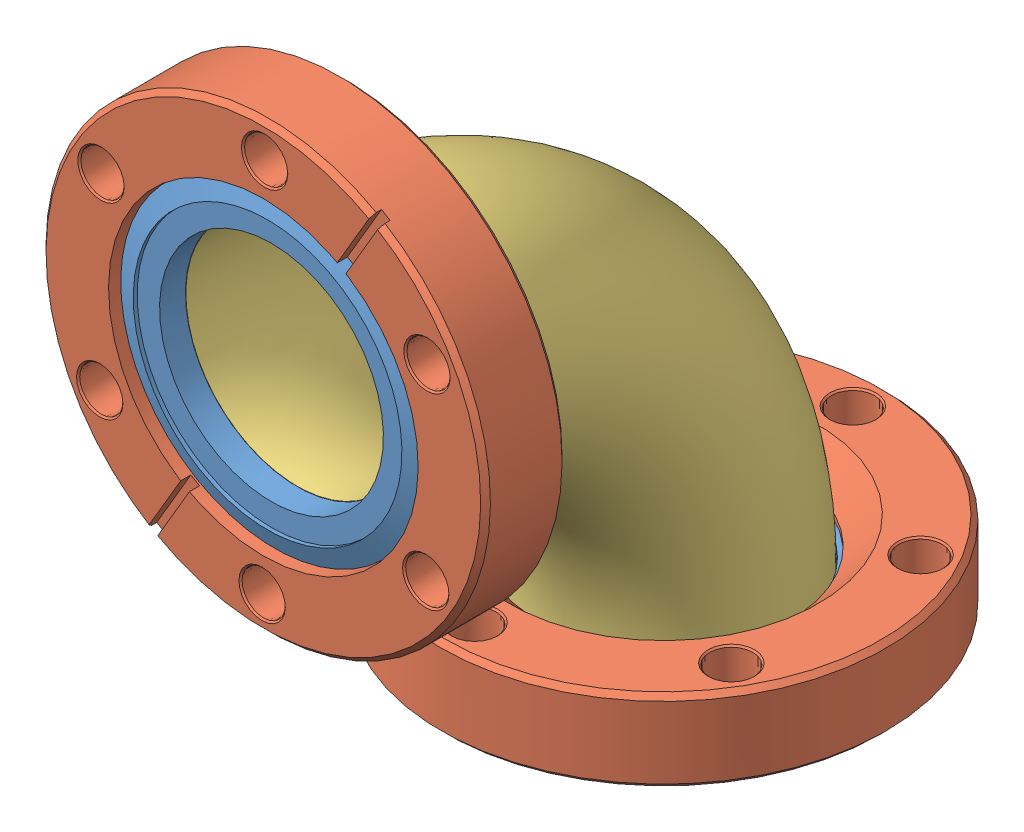
SolidWorks assembly 403002, configuration Default. Lengths in mm.
Overall size (94.6 97.36 109.76).
5 component instances, 3 part files, 0 mates.
Components (placement in the parent):
- 910014-1: 910014 [Default] at origin size (48.06 48.06 6.96)
- 915002-1: 915002 [Default] at (0 -49.7586 -54.8386) x (0 -1 0) z (0.495758 0 0.868461) size (12.7 69.34 69.34)
- 915002-2: 915002 [Default] at (0 0 -5.08) x (0 0 1) z (-0.999978 0.006622 0) size (12.7 69.34 69.34)
- 403502-1: 403502 [Default] at (0 -57.15 2.3114) x (0 1 0) z (0 0 1) size (77.27 39.99 77.27)
- 910014-2: 910014 [Default] at (0 -54.8386 -54.8386) x (1 0 0) z (0 -1 0) size (48.06 48.06 6.96)
